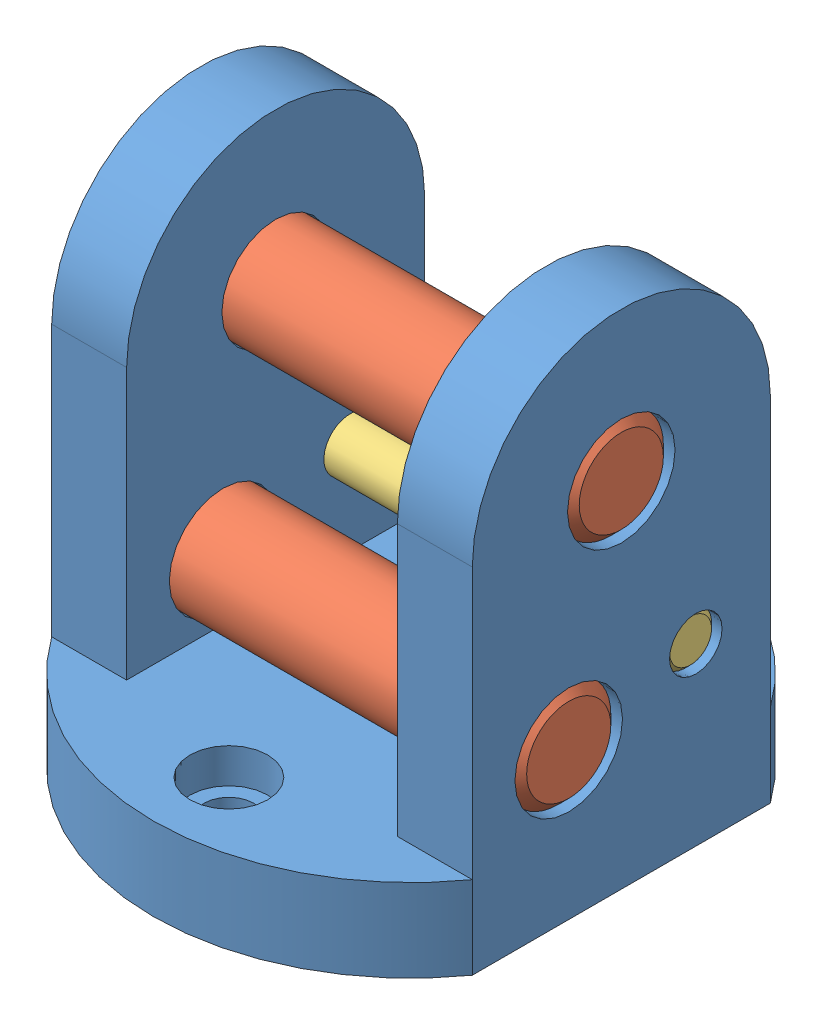
SolidWorks assembly knuckle_block, configuration Default. Lengths in mm.
Overall size (25.72 30.39 31.13).
4 component instances, 3 part files, 8 mates.
Components (placement in the parent):
- f_k1-1: f_k1 [Default] at (-19.0067 19.7155 0.1178) size (25.4 30.39 31.13)
- 98381A542-1: 98381A542 [98381A542] at (-19.0067 7.2382 3.2928) size (25.4 6.35 6.35)
- 98381A475-1: 98381A475 [98381A475] at (-19.3242 8.953 -4.3822) x (1 0 0) z (0 0.998042 -0.062554) size (25.4 3.17 3.17)
- 98381A542-2: 98381A542 [98381A542] at (-19.0067 19.7155 0.1178) size (25.4 6.35 6.35)
Mates (geometry in assembly coordinates):
- Concentric9: concentric aligned: circle of f_k1-1; circle of 98381A542-1
- Coincident9: coincident aligned: plane of f_k1-1 through (-31.7067 19.7155 0.1178) normal (-1 0 0); plane of 98381A542-1 through (-31.7067 7.2382 3.2928) normal (-1 0 0)
- Coincident10: coincident anti-aligned: circle of f_k1-1; circle of 98381A475-1
- Parallel1: parallel aligned: plane of f_k1-1 through (-31.7067 19.7155 0.1178) normal (-1 0 0); plane of 98381A475-1 through (-32.0242 8.953 -4.3822) normal (-1 0 0)
- Concentric11: concentric anti-aligned: circle of f_k1-1; circle of 98381A542-2
- Coincident12: coincident aligned: plane of f_k1-1 through (-31.7067 19.7155 0.1178) normal (-1 0 0); plane of 98381A542-2 through (-31.7067 19.7155 0.1178) normal (-1 0 0)
- Concentric17: concentric aligned: circle of f_k1-1; circle of ?
- Coincident17: coincident anti-aligned: plane of f_k1-1 through (-19.0067 -1.6368 0.1178) normal (0 -1 0); plane of ? through (-19.0067 -1.6368 -10.8822) normal (0 1 0)
